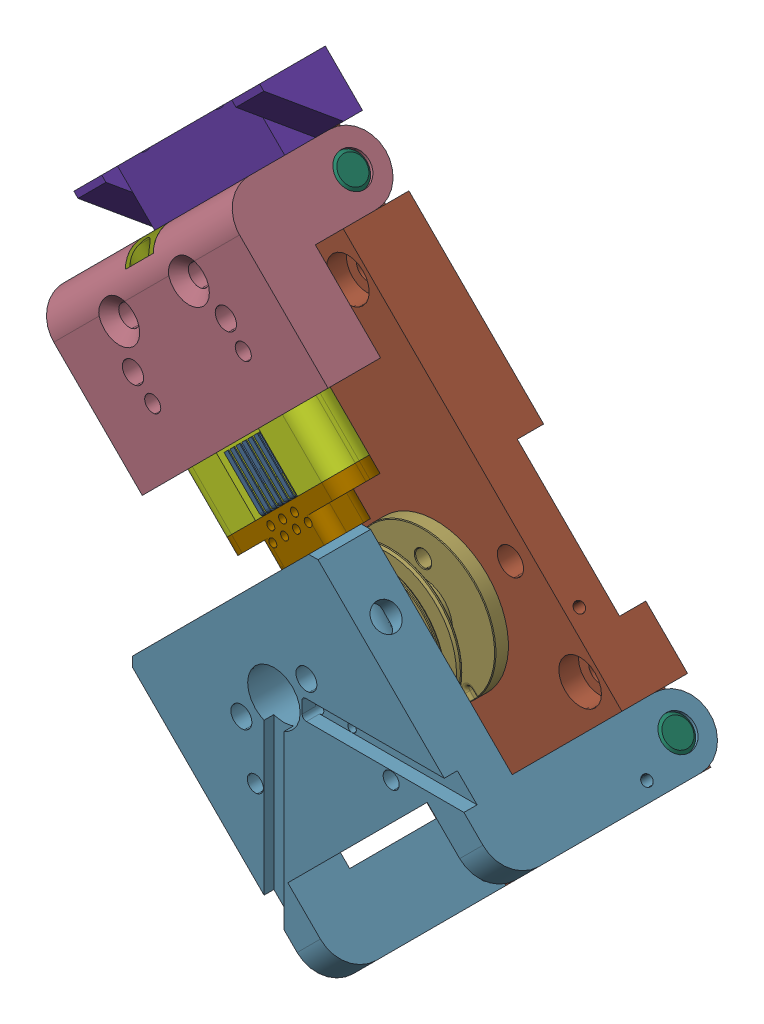
SolidWorks assembly TO92-UF, configuration Default. Lengths in mm.
Overall size (90.51 90.51 34.7).
56 component instances, 17 part files, 0 mates.
Components (placement in the parent):
- TO92-UF.stp-1: TO92-UF.stp [Default] at origin size (90.51 90.51 34.7)
  - 000000015218.stp-1: 000000015218.stp [Default] at (-22.7568 22.6056 127.861) x (0.707107 0.707107 0) z (0.707107 -0.707107 0) size (25.4 6.6 27.8)
    - 000000016371.stp-1: 000000016371.stp [Default] at (0 0.07 25.9) x (1 0 0) z (0 -1 0) size (8.03 27.25 1.76)
      - 000000016370 .stp-1: 000000016370 .stp [Default] at origin size (8.03 26.85 0.34)
      - 000000014948 .stp-1: 000000014948 .stp [Default] at (0 0.03 0.19) size (2.92 2.32 0.6)
      - 000000015182 .stp-1: 000000015182 .stp [Default] at (2.015 -3.574 0.575) x (0 -1 0) z (0 0 1) size (0.82 1.62 0.82)
      - 000000015182 .stp-2: 000000015182 .stp [Default] at (-2.015 -3.574 0.575) x (0 -1 0) z (0 0 -1) size (0.82 1.62 0.82)
      - 000000016372 .stp-1: 000000016372 .stp [Default] at (0 0 -0.47) size (7.33 7.35 1.75)
      - 000000015194 .stp-1: 000000015194 .stp [Default] at (0 0.03 0.17) x (-1 0 0) z (0 0 1) size (2.92 2.32 0.02)
      - 000000015228 .stp-1: 000000015228 .stp [Default] at (-2.015 -3.574 0.17) size (1.78 0.98 0.1)
      - 000000015228 .stp-2: 000000015228 .stp [Default] at (2.015 -3.574 0.17) x (-1 0 0) z (0 0 1) size (1.78 0.98 0.1)
    - 000000015924 .stp-1: 000000015924 .stp [Default] at (22.2208 -27.2583 0) size (25.4 6.6 8.45)
    - 000000015280 .stp-1: 000000015280 .stp [Default] at (-2.54 0 14.45) x (-0.692859 0.721073 0) z (0 0 -1) size (1.5 1.5 7)
    - 000000015280 .stp-2: 000000015280 .stp [Default] at (2.54 0 14.45) x (0.950765 0.309914 0) z (0 0 -1) size (1.5 1.5 7)
    - 000000016660 .stp-1: 000000016660 .stp [Default] at (0 0 8.45) size (25.4 6.6 17.7)
    - 000000002174 .stp-1: 000000002174 .stp [Default] at (0 2.625 19.93) x (1 0 0) z (0 -1 0) size (0.8 12.56 2.79)
    - 000000002174 .stp-2: 000000002174 .stp [Default] at (0 -2.625 19.93) x (-1 0 0) z (0 1 0) size (0.8 12.56 2.79)
    - 000000002174 .stp-3: 000000002174 .stp [Default] at (1.27 2.625 19.93) x (1 0 0) z (0 -1 0) size (0.8 12.56 2.79)
    - 000000002174 .stp-4: 000000002174 .stp [Default] at (1.27 -2.625 19.93) x (-1 0 0) z (0 1 0) size (0.8 12.56 2.79)
    - 000000002174 .stp-5: 000000002174 .stp [Default] at (2.54 2.625 19.93) x (1 0 0) z (0 -1 0) size (0.8 12.56 2.79)
    - 000000002174 .stp-6: 000000002174 .stp [Default] at (2.54 -2.625 19.93) x (-1 0 0) z (0 1 0) size (0.8 12.56 2.79)
    - 000000002174 .stp-7: 000000002174 .stp [Default] at (3.81 2.625 19.93) x (1 0 0) z (0 -1 0) size (0.8 12.56 2.79)
    - 000000002174 .stp-8: 000000002174 .stp [Default] at (3.81 -2.625 19.93) x (-1 0 0) z (0 1 0) size (0.8 12.56 2.79)
    - 000000002174 .stp-9: 000000002174 .stp [Default] at (-1.27 2.625 19.93) x (1 0 0) z (0 -1 0) size (0.8 12.56 2.79)
    - 000000002174 .stp-10: 000000002174 .stp [Default] at (-1.27 -2.625 19.93) x (-1 0 0) z (0 1 0) size (0.8 12.56 2.79)
    - 000000002174 .stp-11: 000000002174 .stp [Default] at (0 2.625 19.93) x (1 0 0) z (0 -1 0) size (0.8 12.56 2.79)
    - 000000002174 .stp-12: 000000002174 .stp [Default] at (0 -2.625 19.93) x (-1 0 0) z (0 1 0) size (0.8 12.56 2.79)
    - 000000002174 .stp-13: 000000002174 .stp [Default] at (1.27 2.625 19.93) x (1 0 0) z (0 -1 0) size (0.8 12.56 2.79)
    - 000000002174 .stp-14: 000000002174 .stp [Default] at (1.27 -2.625 19.93) x (-1 0 0) z (0 1 0) size (0.8 12.56 2.79)
    - 000000002174 .stp-15: 000000002174 .stp [Default] at (2.54 2.625 19.93) x (1 0 0) z (0 -1 0) size (0.8 12.56 2.79)
    - 000000002174 .stp-16: 000000002174 .stp [Default] at (2.54 -2.625 19.93) x (-1 0 0) z (0 1 0) size (0.8 12.56 2.79)
    - 000000002174 .stp-17: 000000002174 .stp [Default] at (-2.54 2.625 19.93) x (1 0 0) z (0 -1 0) size (0.8 12.56 2.79)
    - 000000002174 .stp-18: 000000002174 .stp [Default] at (-2.54 -2.625 19.93) x (-1 0 0) z (0 1 0) size (0.8 12.56 2.79)
    - 000000002174 .stp-19: 000000002174 .stp [Default] at (-1.27 2.625 19.93) x (1 0 0) z (0 -1 0) size (0.8 12.56 2.79)
    - 000000002174 .stp-20: 000000002174 .stp [Default] at (-1.27 -2.625 19.93) x (-1 0 0) z (0 1 0) size (0.8 12.56 2.79)
    - 000000002174 .stp-21: 000000002174 .stp [Default] at (0 2.625 19.93) x (1 0 0) z (0 -1 0) size (0.8 12.56 2.79)
    - 000000002174 .stp-22: 000000002174 .stp [Default] at (0 -2.625 19.93) x (-1 0 0) z (0 1 0) size (0.8 12.56 2.79)
    - 000000002174 .stp-23: 000000002174 .stp [Default] at (1.27 2.625 19.93) x (1 0 0) z (0 -1 0) size (0.8 12.56 2.79)
    - 000000002174 .stp-24: 000000002174 .stp [Default] at (1.27 -2.625 19.93) x (-1 0 0) z (0 1 0) size (0.8 12.56 2.79)
    - 000000002174 .stp-25: 000000002174 .stp [Default] at (-3.81 2.625 19.93) x (1 0 0) z (0 -1 0) size (0.8 12.56 2.79)
    - 000000002174 .stp-26: 000000002174 .stp [Default] at (-3.81 -2.625 19.93) x (-1 0 0) z (0 1 0) size (0.8 12.56 2.79)
    - 000000002174 .stp-27: 000000002174 .stp [Default] at (-2.54 2.625 19.93) x (1 0 0) z (0 -1 0) size (0.8 12.56 2.79)
    - 000000002174 .stp-28: 000000002174 .stp [Default] at (-2.54 -2.625 19.93) x (-1 0 0) z (0 1 0) size (0.8 12.56 2.79)
    - 000000002174 .stp-29: 000000002174 .stp [Default] at (-1.27 2.625 19.93) x (1 0 0) z (0 -1 0) size (0.8 12.56 2.79)
    - 000000002174 .stp-30: 000000002174 .stp [Default] at (-1.27 -2.625 19.93) x (-1 0 0) z (0 1 0) size (0.8 12.56 2.79)
    - 000000002174 .stp-31: 000000002174 .stp [Default] at (0 2.625 19.93) x (1 0 0) z (0 -1 0) size (0.8 12.56 2.79)
    - 000000002174 .stp-32: 000000002174 .stp [Default] at (0 -2.625 19.93) x (-1 0 0) z (0 1 0) size (0.8 12.56 2.79)
  - 000000008258 .stp-1: 000000008258 .stp [Default] at (-14.2391 13.0224 119.241) x (0.707107 -0.707107 0) z (0 0 -1) size (80 40 10)
  - 07226_0012_3 .stp-1: 07226_0012_3 .stp [Default] at (-4.4074 4.2562 128.541) x (0 0 -1) z (0.707107 0.707107 0) size (8.51 22 22)
  - 07226_0012_3 .stp-2: 07226_0012_3 .stp [Default] at (-4.4074 4.2562 126.841) x (0 0 1) z (0 -1 0) size (8.51 22 22)
  - 000000010164 .stp-1: 000000010164 .stp [Default] at (-31.2598 31.1086 127.491) x (-0.707107 -0.707107 0) z (0 0 1) size (40 24.05 22.26)
  - 000000013670.stp-1: 000000013670.stp [Default] at (2.1333 -2.2846 126.641) x (0.707107 0.707107 0) z (0 0 1) size (40 41.5 34.6)
  - 000000010184 .stp-1: 000000010184 .stp [Default] at (13.2703 -13.4215 114.241) x (0.5 -0.5 -0.707107) z (0.707107 0.707107 0) size (5 5 40)
  - 000000010184 .stp-2: 000000010184 .stp [Default] at (-36.2272 36.076 114.241) x (0.5 -0.5 -0.707107) z (0.707107 0.707107 0) size (5 5 40)
  - 000000013904 .stp-1: 000000013904 .stp [Default] at (-34.4594 34.3082 121.991) x (-0.707107 -0.707107 0) z (-0.707107 0.707107 0) size (27 10.05 15)
  - 000000014057 .stp-1: 000000014057 .stp [Default] at (-42.5912 42.4399 119.241) x (-0.707107 -0.707107 0) z (0 0 1) size (40 8 10)
